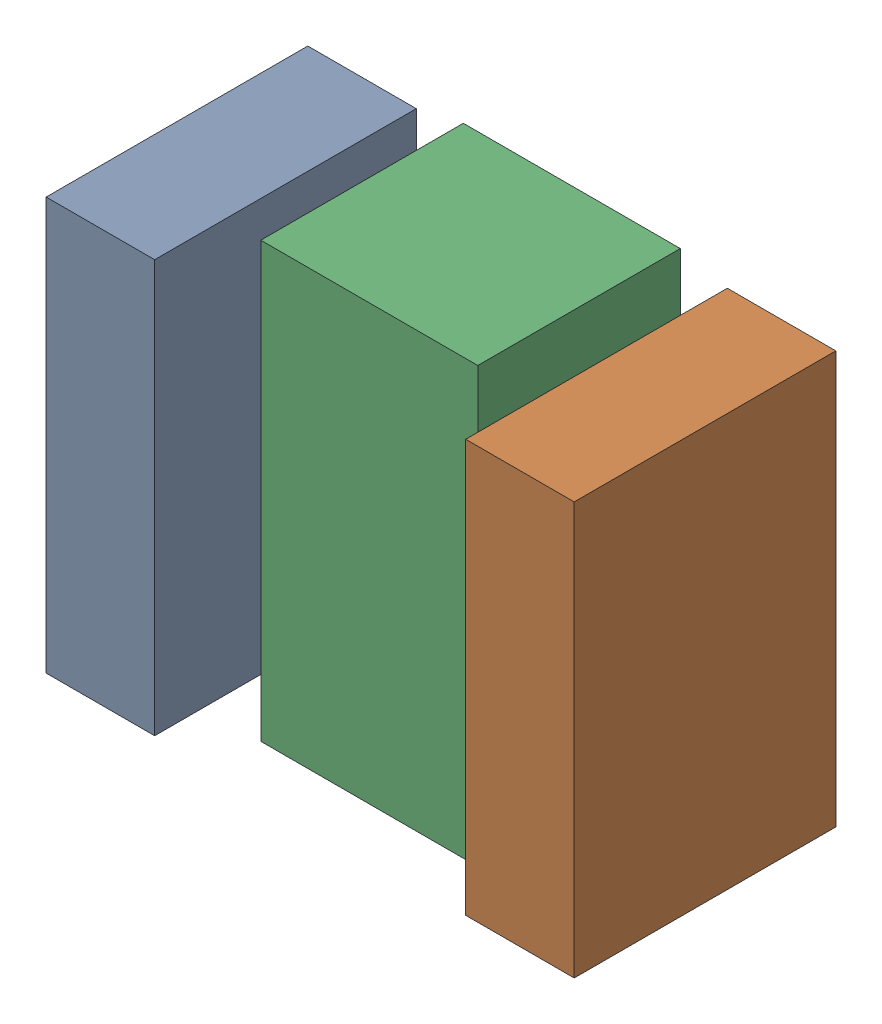
SolidWorks assembly C7_Motor_8Kanaloa_v2.0.0_Motor, configuration Default. Lengths in mm.
Overall size (3.65 3 1.81).
6 component instances, 2 part files, 0 mates.
Components (placement in the parent):
- 334788400-1: 334788400 [Default] at (144.866 139.319 0) size (0.75 2.85 1.81)
  - Extruded_5-1: Extruded_5 [Default] at origin size (0.75 2.85 1.81)
- 334788400-2: 334788400 [Default] at (147.766 139.319 0) size (0.75 2.85 1.81)
  - Extruded_5-1: Extruded_5 [Default] at origin size (0.75 2.85 1.81)
- 334788656-1: 334788656 [Default] at (146.316 139.319 0) size (1.5 3 1.4)
  - Extruded_1-1: Extruded_1 [Default] at origin size (1.5 3 1.4)
